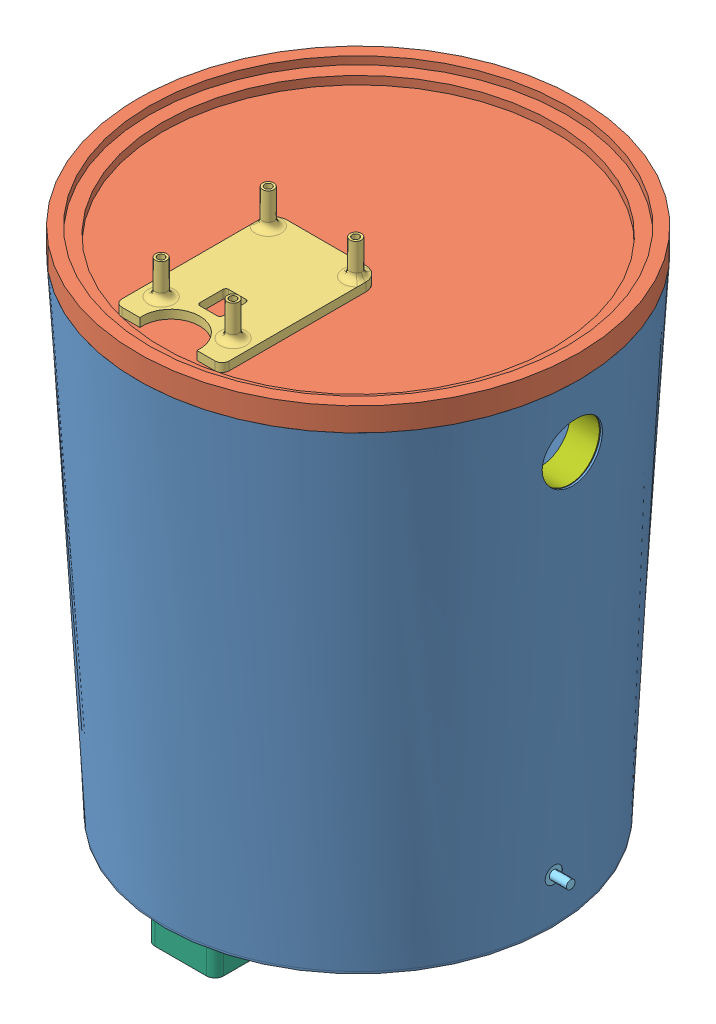
SolidWorks assembly base_link, configuration Valor predeterminado. Lengths in mm.
Overall size (309.11 407.68 309.11).
13 component instances, 7 part files, 25 mates.
Components (placement in the parent):
- corpo-1: corpo [Valor predeterminado] at origin size (307.81 340.4 307.81)
- tampa-1: tampa [Valor predeterminado] at (0 339 0) x (0.003598 0 0.999994) z (-0.999994 0 0.003598) size (308 16.4 308)
- Plataforma Lidar-1: Plataforma Lidar [Valor predeterminado] at (0 356.28 128.9319) x (0 0 1) z (-1 0 0) size (110.46 30 75)
- Montagem_motor-1: Montagem_motor [Valor predeterminado] at (5.3444 13.461 11.8318) x (0 0 1) z (-1 0 0) size (70 44 95)
  - Capa para o motor-1: Capa para o motor [Valor predeterminado] at (-31.8318 -13.461 70.9319) size (70 44 68.53)
  - motor-1: motor [Valor predeterminado] at (-11.8318 10.539 135.8679) size (37 37 95)
- Montagem_motor-2: Montagem_motor [Valor predeterminado] at (-5.3452 13.461 -11.8234) x (-0.000059 0 -1) z (1 0 -0.000059) size (70 44 95)
  - Capa para o motor-1: Capa para o motor [Valor predeterminado] at (-31.8318 -13.461 70.9319) size (70 44 68.53)
  - motor-1: motor [Valor predeterminado] at (-11.8318 10.539 135.8679) size (37 37 95)
- suporte_caster-1: suporte_caster [Valor predeterminado] at (0 -1.4 -100) x (1 0 0) z (0 -1 0) size (48 48 26)
- suporte_caster-2: suporte_caster [Valor predeterminado] at (0 -1.4 100) x (1 0 0) z (0 -1 0) size (48 48 26)
- Plataforma-1: Plataforma [Valor predeterminado] at (-1.07 38.9294 123.9851) size (26.18 86.84 114)
- Plataforma-2: Plataforma [Valor predeterminado] at (1.07 38.9294 -123.9851) x (-1 0 0) z (0 0 -1) size (26.18 86.84 114)
Mates (geometry in assembly coordinates):
- Concêntrico1: concentric: circle of corpo-1; circle of tampa-1
- Bloquear2: lock: unknown of corpo-1; unknown of tampa-1
- Distância2: distance = 6 mm anti-aligned: plane of tampa-1 through (0 344.28 0) normal (0 1 0); plane of Plataforma Lidar-1 through (0 350.28 130.7584) normal (0 -1 0)
- Coincidente4: coincident: cylinder of tampa-1 through (0 344.28 0) axis (0 1 0) radius 136.5; line of Plataforma Lidar-1 through (32.5 350.28 132.5745) axis (0 1 0)
- Coincidente5: coincident: cylinder of tampa-1 through (0 344.28 0) axis (0 1 0) radius 136.5; line of Plataforma Lidar-1 through (-32.5 350.28 132.5745) axis (0 1 0)
- Paralelo1: parallel: line of Plataforma Lidar-1 through (-27.5 356.28 22.1128) axis (1 0 0)
- Coincidente12: coincident: plane of corpo-1 through (0 0 0) normal (0 1 0); plane of Montagem_motor-1/Capa para o motor-1 through (-130.5874 0 -20) normal (0 -1 0)
- Concêntrico2: concentric aligned: cylinder of corpo-1 through (-153.9029 31.2 0) axis (1 0 0) radius 6; cylinder of Montagem_motor-1/motor-1 through (-136.5234 31.2 0) axis (1 0 0) radius 6
- Tangente4: tangent: curve of corpo-1; circle of Montagem_motor-1/motor-1
- Coincidente13: coincident anti-aligned: plane of corpo-1 through (0 0 0) normal (0 1 0); plane of Montagem_motor-2/Capa para o motor-1 through (130.5886 0 20.0003) normal (0 -1 0)
- Tangente5: tangent: curve of corpo-1; circle of Montagem_motor-2/motor-1
- Coincidente14: coincident anti-aligned: plane of corpo-1 through (0 -1.4 0) normal (0 -1 0); plane of suporte_caster-1 through (0 -1.4 -100) normal (0 1 0)
- Coincidente15: coincident anti-aligned: plane of corpo-1 through (0 -1.4 0) normal (0 -1 0); plane of suporte_caster-2 through (0 -1.4 100) normal (0 1 0)
- Concêntrico3: concentric aligned: cylinder of corpo-1 through (15.6 0 115.6) axis (0 -1 0) radius 3; cylinder of suporte_caster-2 through (15.6 -1.4 115.6) axis (0 -1 0) radius 3
- Concêntrico4: concentric aligned: cylinder of corpo-1 through (-15.6 0 84.4) axis (0 -1 0) radius 3; cylinder of suporte_caster-2 through (-15.6 -1.4 84.4) axis (0 -1 0) radius 3
- Concêntrico5: concentric aligned: cylinder of corpo-1 through (15.6 0 -84.4) axis (0 -1 0) radius 3; cylinder of suporte_caster-1 through (15.6 -1.4 -84.4) axis (0 -1 0) radius 3
- Concêntrico6: concentric aligned: cylinder of corpo-1 through (-15.6 0 -115.6) axis (0 -1 0) radius 3; cylinder of suporte_caster-1 through (-15.6 -1.4 -115.6) axis (0 -1 0) radius 3
- Concêntrico8: concentric aligned: cylinder of corpo-1 through (-153.9029 294 0) axis (1 0 0) radius 21; cylinder of Plataforma-1 through (-139.1786 294 0) axis (1 0 0) radius 21
- Paralelo2: parallel aligned: plane of Plataforma-1 through (-114.2816 342.576 -122.91) normal (1 0 0)
- Paralelo3: parallel anti-aligned: plane of corpo-1 through (0 0 0) normal (0 1 0); plane of Plataforma-1 through (-139.1776 250.7446 123.9851) normal (0 -1 0)
- Concêntrico9: concentric anti-aligned: cylinder of corpo-1 through (-153.9029 294 0) axis (1 0 0) radius 21; cylinder of Plataforma-2 through (152.8971 294 0) axis (-1 0 0) radius 21
- Paralelo4: parallel anti-aligned: plane of Plataforma-2 through (128 342.576 122.91) normal (-1 0 0)
- Paralelo6: parallel anti-aligned: plane of corpo-1 through (0 0 0) normal (0 1 0); plane of Plataforma-2 through (152.8961 250.7446 -123.9851) normal (0 -1 0)
- Distância4: distance = 127 mm anti-aligned: plane of Plataforma-2 through (127 342.576 122.91) normal (-1 0 0)
- Distância5: distance = 127 mm aligned: plane of Plataforma-1 through (-127 342.576 -122.91) normal (1 0 0)
